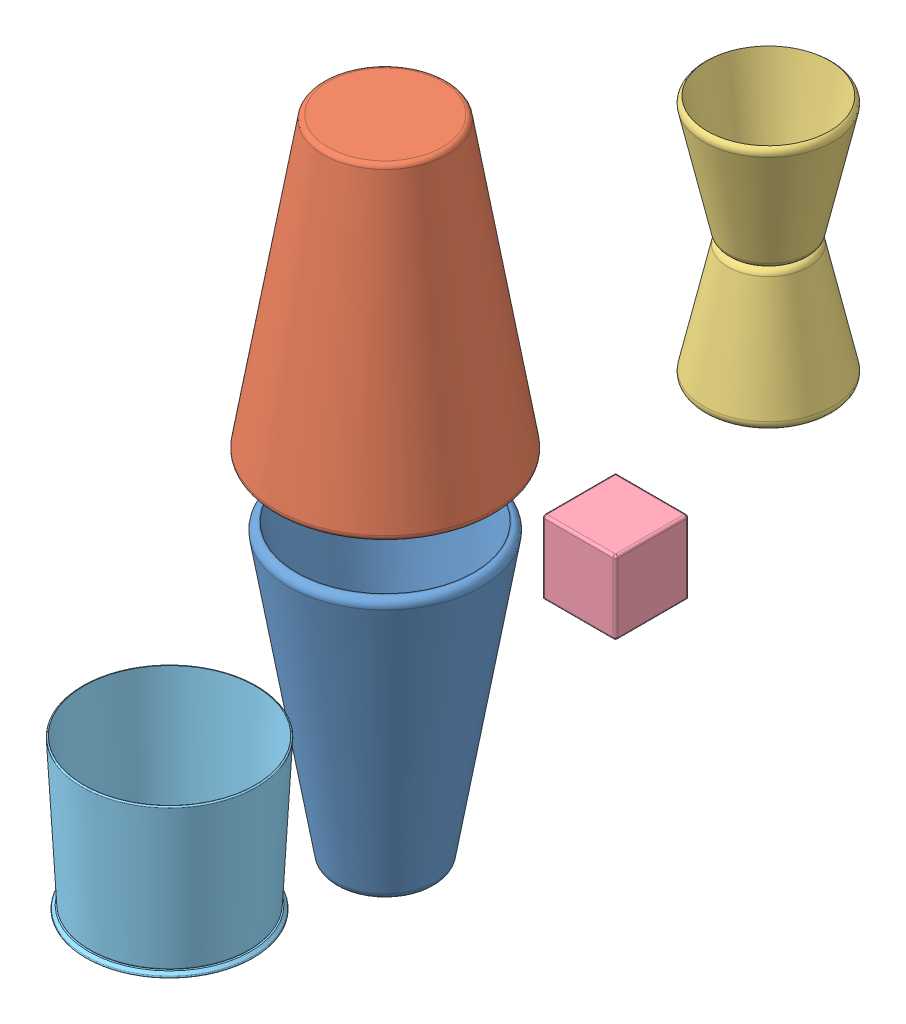
SolidWorks assembly Assem1, configuration Default. Lengths in mm.
Overall size (1181.37 2642.17 2649.76).
5 component instances, 5 part files, 1 mates.
Components (placement in the parent):
- Bot Shaker-1: Bot Shaker [Default] at (-232.4852 -265.5998 1202.0684) size (789.17 1200 789.17)
- Top Shaker-1: Top Shaker [Default] at (-232.4852 1371.9161 1202.0684) x (-0.998464 0 -0.055403) z (-0.055403 0 0.998464) size (894.14 1200 894.14)
- jigg-1: jigg [Default] at (213.6008 1604.5241 81.0114) size (528.27 1000 528.27)
- ice-1: ice [Default] at (-24.5774 165.5721 317.9584) size (300 300 300)
- Glass Cup-1: Glass Cup [Default] at (-56.4955 131.1353 2110.1073) size (713.06 619.15 713.06)
Mates (geometry in assembly coordinates):
- Concentric1: concentric anti-aligned: circle of Bot Shaker-1; circle of Top Shaker-1
